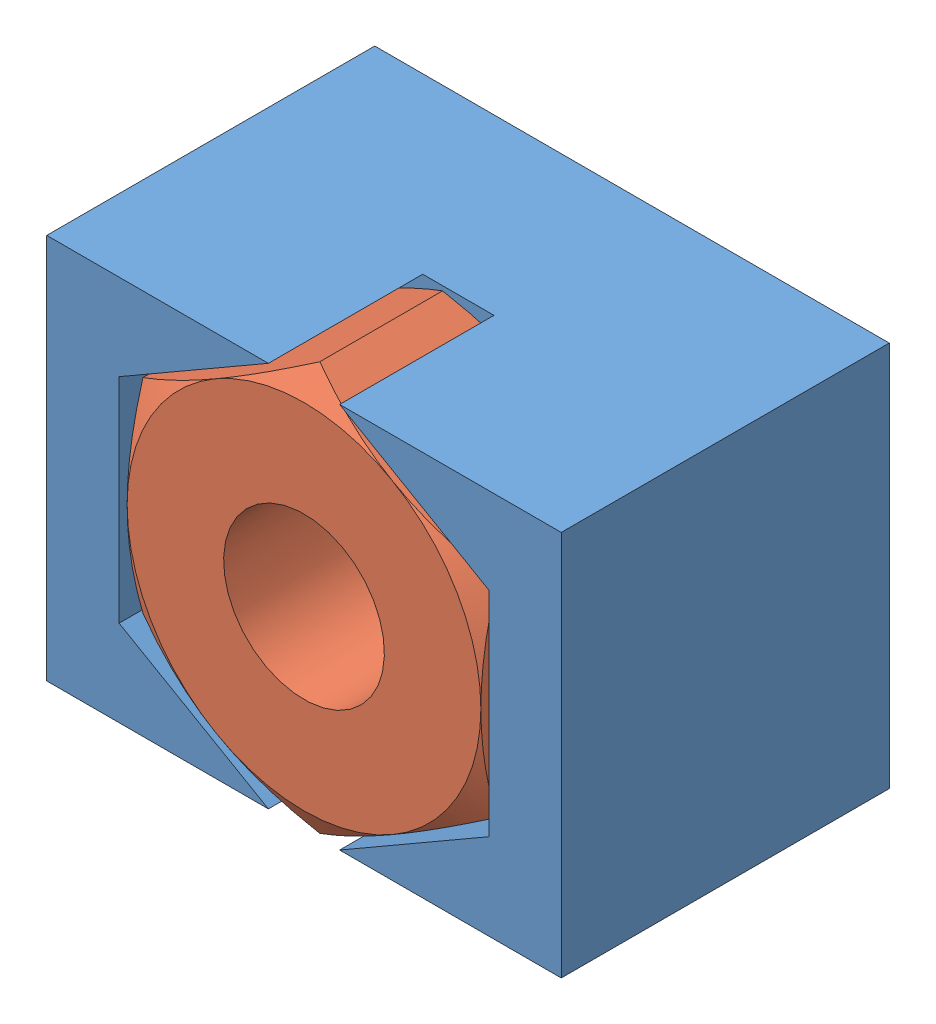
SolidWorks assembly Assembly m3-nut-adapter + Nut DIN 934 - M3, configuration Valor predeterminado. Lengths in mm.
Overall size (8.25 7.94 5.1).
2 component instances, 2 part files, 6 mates.
Components (placement in the parent):
- m3-nut-adapter-1: m3-nut-adapter [Valor predeterminado] at origin size (8 6 5.1)
- Nut DIN 934 - M3-1: Nut DIN 934 - M3 [Valor predeterminado] at (0 0 3.9) x (0 0 1) z (-0.866025 -0.5 0) size (2.4 5.5 6.35)
Mates (geometry in assembly coordinates):
- Concêntrico1: concentric: cylinder of assembly; cylinder of assembly; cylinder of m3-nut-adapter-1 through (0 0 -5.3033) axis (0 0 1) radius 1.875; cylinder of Nut DIN 934 - M3-1 through (0 0 5.1) axis (0 0 -1) radius 1.25
- Paralelo1: parallel: plane of assembly; plane of assembly; plane of m3-nut-adapter-1 through (2.875 -1.6599 2.7) normal (-1 0 0); plane of Nut DIN 934 - M3-1 through (2.75 -1.5877 5.1) normal (1 0 0)
- Coincidente2: coincident: plane of assembly; plane of assembly; plane of m3-nut-adapter-1 through (0 0 2.7) normal (0 0 1); plane of Nut DIN 934 - M3-1 through (2.75 -1.5877 2.7) normal (0 0 -1)
- Simétrico1: symmetric: plane of assembly; plane of assembly; plane of m3-nut-adapter-1 through (4 3 5.1) normal (1 0 0); plane of m3-nut-adapter-1 through (-4 3 5.1) normal (-1 0 0); plane of assembly
- Simétrico2: symmetric: plane of assembly; plane of assembly; plane of m3-nut-adapter-1 through (-4 -3 5.1) normal (0 -1 0); plane of m3-nut-adapter-1 through (-4 3 5.1) normal (0 1 0); plane of assembly
- Coincidente3: coincident: plane of assembly through (0 0 0) normal (0 0 1); plane of m3-nut-adapter-1 through (0 0 0) normal (0 0 -1); plane of assembly
